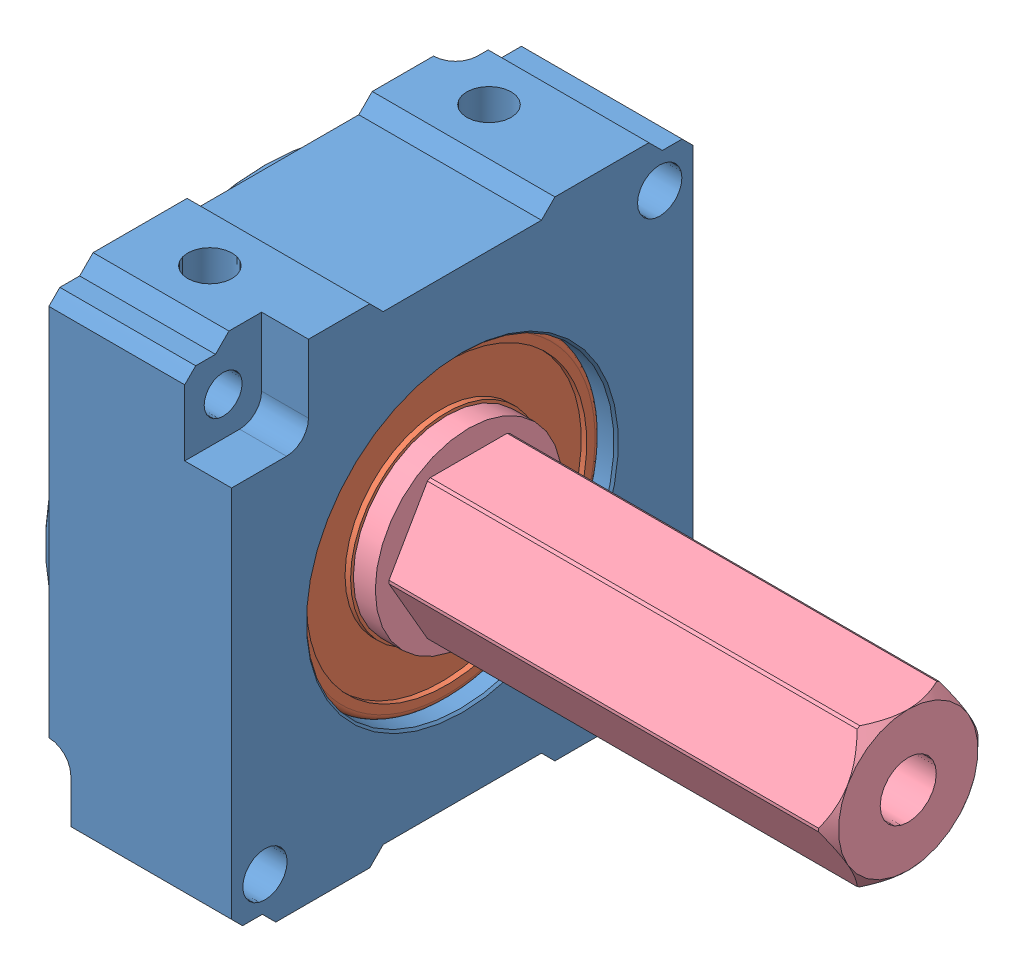
SolidWorks assembly Hex_output, configuration Default. Lengths in mm.
Overall size (72.2 49.05 49.3).
15 component instances, 8 part files, 0 mates.
Components (placement in the parent):
- 217-2625-026 Rev1-1: 217-2625-026 Rev1 [Default] at (-6.5 22.225 0) x (0 -1 0) z (-1 0 0) size (44.45 42 18.13)
- 217-2742-001 Rev4-1: 217-2742-001 Rev4 [Default] at (0.2002 22.225 0) x (1 0 0) z (0 -0.092627 0.995701) size (7 28 28)
- 217-2742-001 Rev4-2: 217-2742-001 Rev4 [Default] at (8.2002 22.225 0) size (7 28 28)
- 217-2625-017 Rev1_9714K61-1: 217-2625-017 Rev1_9714K61 [Default] at (7.42 22.3002 -0.342) x (0 0.56703 0.823697) z (0 -0.823697 0.56703) size (28.51 4.98 30.18)
- 217-2625-003 Rev1-1: 217-2625-003 Rev1 [Default] at (7.4478 22.225 0) x (0 -1 0) z (1 0 0) size (17 17 64.12)
- 217-2625-018 Rev1_98541A410-1: 217-2625-018 Rev1_98541A410 [Default] at (-0.7046 22.225 0) x (1 0 0) z (0 -0.017452 0.999848) size (1 19.6 17.4)
- 217-2820 Rev1_Public-1: 217-2820 Rev1_Public [Default] at (-4.6546 22.225 0) x (0 -0.456494 0.889726) z (-1 0 0) size (39.26 38.9 12.7)
  - 217-2625-100-1: 217-2625-100 [Default] at origin size (39.26 38.9 12.7)
    - 217-2625-008 Rev1-1: 217-2625-008 Rev1 [Default] at origin size (34.7 34.7 4.7)
    - 217-2625-010 Rev1-1: 217-2625-010 Rev1 [Default] at (0 10.193 3.65) x (0.999813 0.019336 0) z (0 0 1) size (4 4 12)
    - 217-2625-010 Rev1-2: 217-2625-010 Rev1 [Default] at (8.691 -5.3258 3.65) size (4 4 12)
    - 217-2625-010 Rev1-3: 217-2625-010 Rev1 [Default] at (-8.691 -5.3258 3.65) size (4 4 12)
    - 217-2625-005 Rev1_Planet_Revolving_Follower01-1: 217-2625-005 Rev1_Planet_Revolving_Follower01 [Default] at (8.691 -5.3258 6.35) x (0.932816 0.360354 0) z (0 0 1) size (16.91 16.92 8)
    - 217-2625-005 Rev1_Planet_Revolving_Follower01-2: 217-2625-005 Rev1_Planet_Revolving_Follower01 [Default] at (-8.691 -5.3258 6.35) x (-0.932788 -0.360426 0) z (0 0 1) size (16.91 16.92 8)
    - 217-2625-005 Rev1_Planet_Revolving_Follower01-3: 217-2625-005 Rev1_Planet_Revolving_Follower01 [Default] at (0 10.193 6.35) x (0.893583 0.448898 0) z (0 0 1) size (16.91 16.92 8)
